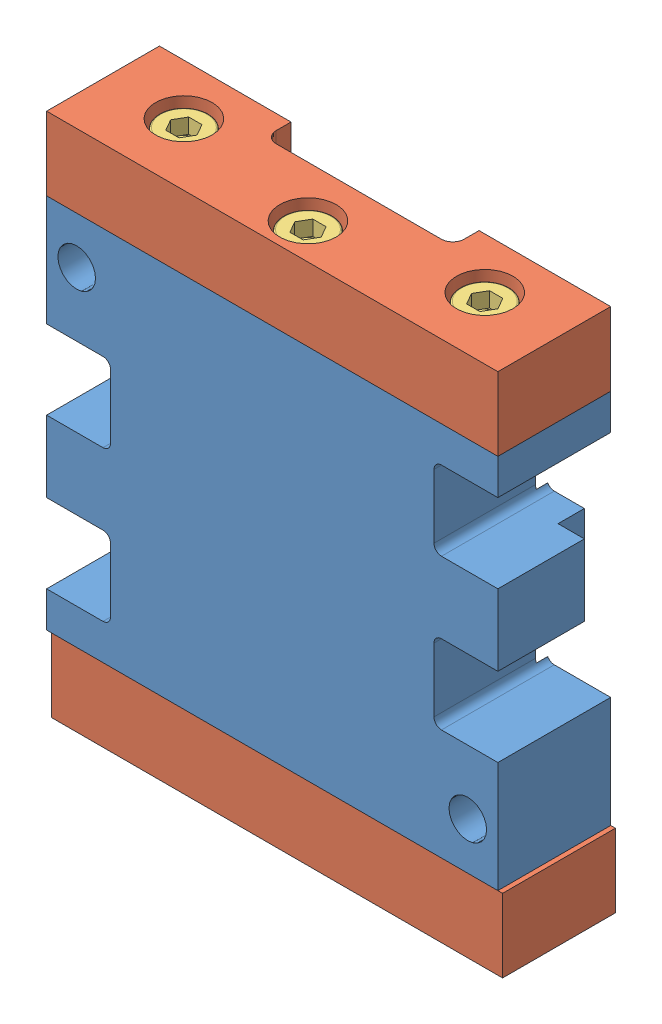
SolidWorks assembly Сборка пуансона, configuration По умолчанию. Lengths in mm.
Overall size (121.25 139 30.34).
9 component instances, 3 part files, 21 mates.
Components (placement in the parent):
- Пуансон-1: Пуансон [По умолчанию] at origin size (120 100 30)
- Боковина Пуансона-1: Боковина Пуансона [По умолчанию] at (121.25 0 30) x (-1 0 0) z (0 -1 0) size (120 30.34 139)
- Боковина Пуансона-2: Боковина Пуансона [По умолчанию] at (0 100 30) x (1 0 0) z (0 1 0) size (120 30.34 139)
- socket head cap screw_iso-2: socket head cap screw_iso [ISO 4762 M8 x 16 - 16N] at (101.25 -17.5 13.5) x (0 1 0) z (0 0 1) size (24 13 13)
- socket head cap screw_iso-3: socket head cap screw_iso [ISO 4762 M8 x 16 - 16N] at (61.25 -17.5 20.5) x (0 1 0) z (0 0 1) size (24 13 13)
- socket head cap screw_iso-4: socket head cap screw_iso [ISO 4762 M8 x 16 - 16N] at (21.25 -17.5 13.5) x (0 1 0) z (0 0 1) size (24 13 13)
- socket head cap screw_iso-5: socket head cap screw_iso [ISO 4762 M8 x 16 - 16N] at (20 117.5 13.5) x (0 -1 0) z (0 0 1) size (24 13 13)
- socket head cap screw_iso-6: socket head cap screw_iso [ISO 4762 M8 x 16 - 16N] at (60 117.5 20.5) x (0 -1 0) z (0 0 1) size (24 13 13)
- socket head cap screw_iso-7: socket head cap screw_iso [ISO 4762 M8 x 16 - 16N] at (100 117.5 13.5) x (0 -1 0) z (0 0 1) size (24 13 13)
Mates (geometry in assembly coordinates):
- Совпадение1: coincident anti-aligned: plane of Пуансон-1 through (0 0 30) normal (0 -1 0); plane of Боковина Пуансона-1 through (121.25 0 30) normal (0 1 0)
- Концентричный1: concentric aligned: cylinder of Пуансон-1 through (101.25 22 13.5) axis (0 -1 0) radius 4; cylinder of Боковина Пуансона-1 through (101.25 0 13.5) axis (0 -1 0) radius 4.5
- Параллельность1: parallel aligned: cylinder of Пуансон-1 through (21.25 22 13.5) axis (0 -1 0) radius 4; cylinder of Боковина Пуансона-1 through (21.25 0 13.5) axis (0 -1 0) radius 4.5
- Параллельность2: parallel aligned: cylinder of Пуансон-1 through (21.25 22 13.5) axis (0 -1 0) radius 4; cylinder of Боковина Пуансона-1 through (21.25 0 13.5) axis (0 -1 0) radius 4.5
- Параллельность3: parallel aligned: cylinder of Пуансон-1 through (21.25 22 13.5) axis (0 -1 0) radius 4; cylinder of Боковина Пуансона-1 through (21.25 0 13.5) axis (0 -1 0) radius 4.5
- Концентричный9: concentric aligned: cylinder of Пуансон-1 through (21.25 22 13.5) axis (0 -1 0) radius 4; cylinder of Боковина Пуансона-1 through (21.25 0 13.5) axis (0 -1 0) radius 4.5
- Совпадение2: coincident anti-aligned: plane of Пуансон-1 through (0 100 30) normal (0 1 0); plane of Боковина Пуансона-2 through (0 100 30) normal (0 -1 0)
- Концентричный10: concentric aligned: cylinder of Пуансон-1 through (20 78 13.5) axis (0 1 0) radius 4; cylinder of Боковина Пуансона-2 through (20 100 13.5) axis (0 1 0) radius 4.5
- Концентричный11: concentric aligned: cylinder of Пуансон-1 through (100 78 13.5) axis (0 1 0) radius 4; cylinder of Боковина Пуансона-2 through (100 100 13.5) axis (0 1 0) radius 4.5
- Концентричный12: concentric aligned: cylinder of Боковина Пуансона-1 through (101.25 0 13.5) axis (0 -1 0) radius 4.5; cylinder of socket head cap screw_iso-2 through (101.25 -49.25 13.5) axis (0 -1 0) radius 6.5
- Совпадение3: coincident anti-aligned: plane of Боковина Пуансона-1 through (101.25 -9.5 13.5) normal (0 -1 0); plane of socket head cap screw_iso-2 through (94.75 -9.5 13.5) normal (0 1 0)
- Концентричный13: concentric aligned: cylinder of Боковина Пуансона-1 through (61.25 0 20.5) axis (0 -1 0) radius 4.5; cylinder of socket head cap screw_iso-3 through (61.25 -49.25 20.5) axis (0 -1 0) radius 6.5
- Совпадение4: coincident anti-aligned: plane of Боковина Пуансона-1 through (61.25 -9.5 20.5) normal (0 -1 0); plane of socket head cap screw_iso-3 through (54.75 -9.5 20.5) normal (0 1 0)
- Концентричный14: concentric aligned: cylinder of Боковина Пуансона-1 through (21.25 0 13.5) axis (0 -1 0) radius 4.5; cylinder of socket head cap screw_iso-4 through (21.25 -49.25 13.5) axis (0 -1 0) radius 6.5
- Совпадение5: coincident anti-aligned: plane of Боковина Пуансона-1 through (21.25 -9.5 13.5) normal (0 -1 0); plane of socket head cap screw_iso-4 through (14.75 -9.5 13.5) normal (0 1 0)
- Концентричный15: concentric aligned: cylinder of Боковина Пуансона-2 through (20 109.5 13.5) axis (0 1 0) radius 7.5; cylinder of socket head cap screw_iso-5 through (20 149.25 13.5) axis (0 1 0) radius 6.5
- Совпадение6: coincident anti-aligned: plane of Боковина Пуансона-2 through (20 109.5 13.5) normal (0 1 0); plane of socket head cap screw_iso-5 through (26.5 109.5 13.5) normal (0 -1 0)
- Концентричный16: concentric aligned: cylinder of Боковина Пуансона-2 through (60 109.5 20.5) axis (0 1 0) radius 7.5; cylinder of socket head cap screw_iso-6 through (60 149.25 20.5) axis (0 1 0) radius 6.5
- Совпадение7: coincident anti-aligned: plane of Боковина Пуансона-2 through (60 109.5 20.5) normal (0 1 0); plane of socket head cap screw_iso-6 through (66.5 109.5 20.5) normal (0 -1 0)
- Концентричный17: concentric aligned: cylinder of Боковина Пуансона-2 through (100 100 13.5) axis (0 1 0) radius 4.5; cylinder of socket head cap screw_iso-7 through (100 149.25 13.5) axis (0 1 0) radius 6.5
- Совпадение8: coincident anti-aligned: plane of Боковина Пуансона-2 through (100 109.5 13.5) normal (0 1 0); plane of socket head cap screw_iso-7 through (106.5 109.5 13.5) normal (0 -1 0)
